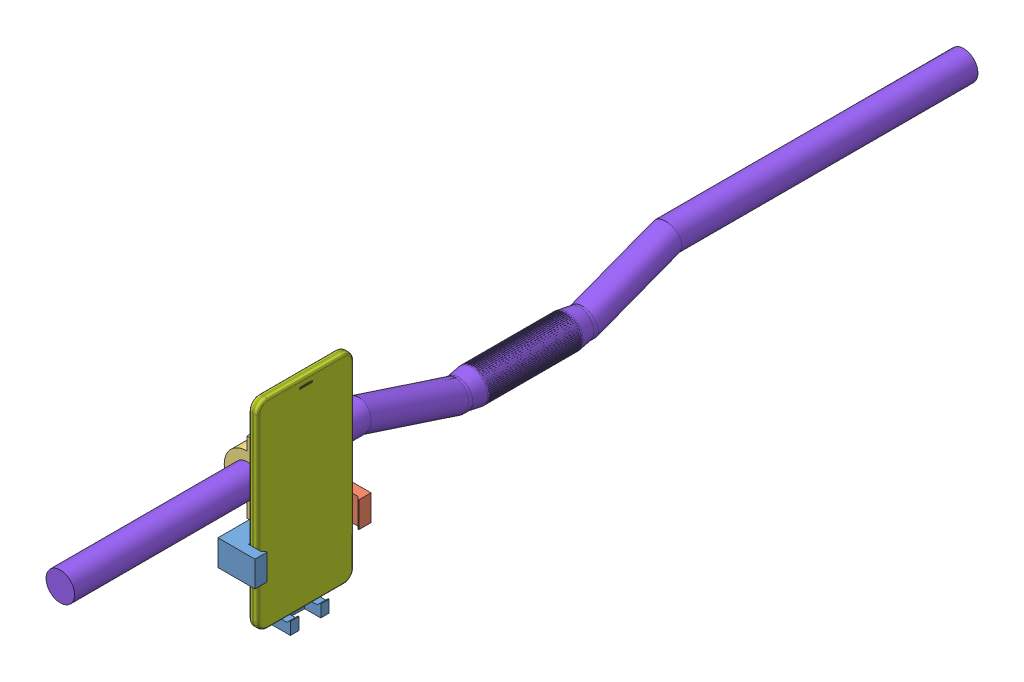
SolidWorks assembly assemblage_avec_smartphone, configuration Défaut. Lengths in mm.
Overall size (51.29 162.52 700).
10 component instances, 8 part files, 21 mates.
Components (placement in the parent):
- supportPrincipal-1: supportPrincipal [Défaut] at (-17.1177 24.6397 119.4443) size (28.69 119.44 57.5)
- bras_mobile-1: bras_mobile [Défaut] at (-13.0073 -20.3046 114.4443) x (0 0 -1) z (0 -1 0) size (47.5 28.69 20)
- attache-1: attache [Défaut] at (-18.0073 24.6397 119.4443) x (0 1 0) z (0 0 1) size (55.2 22.6 30)
- Vis à tête cylindrique à six pans creux Chc M4 - 20-1: Vis à tête cylindrique à six pans creux Chc M4 - 20 [Défaut] at (-18.0073 47.2397 134.4443) x (0 0 -1) z (1 0 0) size (7 7 24)
- Ecrou M4-1: Ecrou M4 [Défaut] at (2.8823 47.2397 134.4443) x (0 0.451623 0.892209) z (1 0 0) size (7 8.08 3.2)
- Vis à tête cylindrique à six pans creux Chc M4 - 20-2: Vis à tête cylindrique à six pans creux Chc M4 - 20 [Défaut] at (-18.0073 2.0397 134.4443) x (0 0 -1) z (1 0 0) size (7 7 24)
- Ecrou M4-2: Ecrou M4 [Défaut] at (2.8823 2.0397 134.4443) x (0 0 -1) z (1 0 0) size (7 8.08 3.2)
- Ressort-1: Ressort [Défaut] at (0.9304 -9.8445 140.9512) x (-0.000033 -0.003935 -0.999992) z (0.987938 0.154851 -0.000642) size (28.7 6.45 6.45)
- smartphone-1: smartphone [Default] at (3.1823 -11.6304 128.7296) x (0 1 0) z (0 0 -1) size (155.13 8 75.53)
- cintre-1: cintre [Défaut] at (-12.178 4.694 -55.5557) x (0 0 -1) z (0.962258 0.27214 0) size (700 43.8 25.4)
Mates (geometry in assembly coordinates):
- Coïncidente1: coincident anti-aligned: plane of supportPrincipal-1 through (-13.0073 34.0839 149.4443) normal (-1 0 0); plane of attache-1 through (-13.0073 34.9397 149.4443) normal (1 0 0)
- Coaxiale1: concentric aligned: cylinder of supportPrincipal-1 through (16.9927 47.2397 134.4443) axis (-1 0 0) radius 2.6; cylinder of attache-1 through (-13.0073 47.2397 134.4443) axis (-1 0 0) radius 2.6
- Coaxiale2: concentric aligned: cylinder of supportPrincipal-1 through (16.9927 2.0397 134.4443) axis (-1 0 0) radius 2.6; cylinder of attache-1 through (-13.0073 2.0397 134.4443) axis (-1 0 0) radius 2.6
- Coïncidente6: coincident anti-aligned: plane of supportPrincipal-1 through (-10.0073 -11.5546 144.4443) normal (0 1 0); plane of bras_mobile-1 through (-5.5073 -11.5546 134.4443) normal (0 -1 0)
- Coïncidente8: coincident aligned: plane of supportPrincipal-1 through (-13.0073 15.1954 149.4443) normal (-1 0 0); plane of bras_mobile-1 through (-13.0073 -20.3046 114.4443) normal (-1 0 0)
- Coaxiale9: concentric anti-aligned: cylinder of supportPrincipal-1 through (16.9927 47.2397 134.4443) axis (-1 0 0) radius 2.6; cylinder of Vis à tête cylindrique à six pans creux Chc M4 - 20-1 through (-18.0073 47.2397 134.4443) axis (1 0 0) radius 2
- Coïncidente15: coincident anti-aligned: plane of attache-1 through (-18.0073 42.2397 149.4443) normal (-1 0 0); plane of Vis à tête cylindrique à six pans creux Chc M4 - 20-1 through (-18.0073 47.2397 134.4443) normal (1 0 0)
- Coaxiale10: concentric anti-aligned: cylinder of Vis à tête cylindrique à six pans creux Chc M4 - 20-1 through (-18.0073 47.2397 134.4443) axis (1 0 0) radius 2; cylinder of Ecrou M4-1 through (-0.3177 47.2397 134.4443) axis (-1 0 0) radius 1.65
- Coïncidente16: coincident anti-aligned: plane of supportPrincipal-1 through (-0.3177 24.6397 119.4443) normal (1 0 0); plane of Ecrou M4-1 through (-0.3177 40.2503 134.0594) normal (-1 0 0)
- Coïncidente17: coincident anti-aligned: plane of attache-1 through (-18.0073 -2.9603 149.4443) normal (-1 0 0); plane of Vis à tête cylindrique à six pans creux Chc M4 - 20-2 through (-18.0073 2.0397 134.4443) normal (1 0 0)
- Coaxiale11: concentric anti-aligned: cylinder of supportPrincipal-1 through (16.9927 2.0397 134.4443) axis (-1 0 0) radius 2.6; cylinder of Vis à tête cylindrique à six pans creux Chc M4 - 20-2 through (-18.0073 2.0397 134.4443) axis (1 0 0) radius 2
- Coïncidente18: coincident anti-aligned: plane of supportPrincipal-1 through (-0.3177 24.6397 119.4443) normal (1 0 0); plane of Ecrou M4-2 through (-0.3177 8.1018 137.9443) normal (-1 0 0)
- Coaxiale12: concentric anti-aligned: cylinder of Vis à tête cylindrique à six pans creux Chc M4 - 20-2 through (-18.0073 2.0397 134.4443) axis (1 0 0) radius 2; cylinder of Ecrou M4-2 through (-0.3177 2.0397 134.4443) axis (-1 0 0) radius 1.65
- Tangent3: tangent anti-aligned: plane of supportPrincipal-1 through (-1.8177 24.6397 119.4443) normal (1 0 0); face of Ressort-1
- Tangent4: tangent anti-aligned: plane of supportPrincipal-1 through (-1.8177 -7.0546 119.4443) normal (0 -1 0); edge_curve of Ressort-1
- Coïncidente19: coincident anti-aligned: plane of supportPrincipal-1 through (15.6823 0.1954 169.4443) normal (0 0 -1); plane of smartphone-1 through (10.1823 -57.3046 169.4443) normal (0 0 1)
- Coïncidente20: coincident anti-aligned: plane of supportPrincipal-1 through (15.6823 -57.3046 149.4443) normal (0 1 0); plane of smartphone-1 through (10.1823 -57.3046 169.4443) normal (0 -1 0)
- Coïncidente21: coincident anti-aligned: plane of supportPrincipal-1 through (3.1823 -57.3046 149.4443) normal (1 0 0); plane of smartphone-1 through (3.1823 -11.6304 128.7296) normal (-1 0 0)
- Coïncidente22: coincident anti-aligned: plane of bras_mobile-1 through (15.6827 -0.3046 94.4443) normal (0 0 1); plane of smartphone-1 through (10.1823 -57.3046 94.4443) normal (0 0 -1)
- Tangent6: tangent aligned: cylinder of attache-1 through (-18.0073 24.6397 149.4443) axis (0 0 -1) radius 10.3; edge_curve of cintre-1
- Distance1: distance = 200 mm anti-aligned: plane of cintre-1 through (-14.6001 13.2581 294.4443) normal (0 0 1); plane of smartphone-1 through (10.1823 -57.3046 94.4443) normal (0 0 -1)
